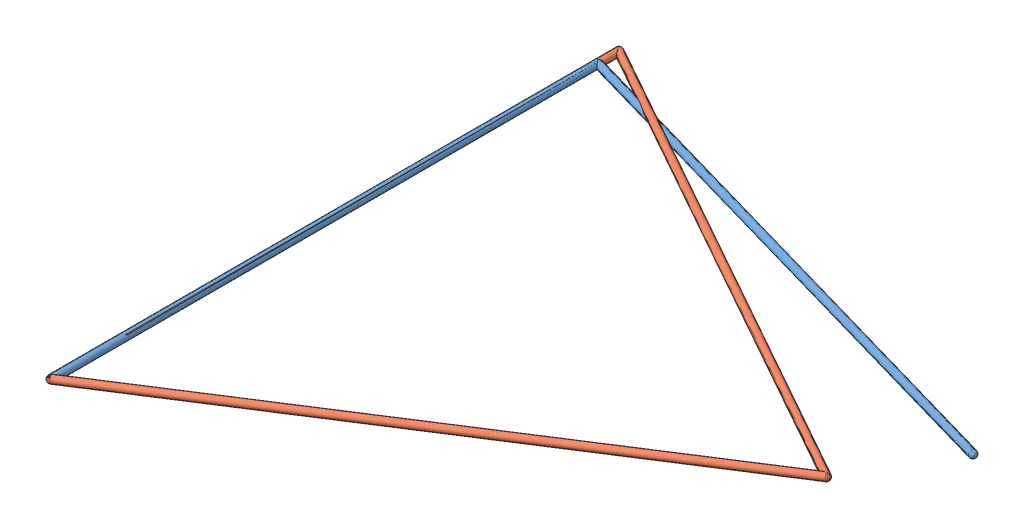
SolidWorks assembly dome_4v_model_1_major_triangle, configuration Default. Lengths in mm.
Overall size (1400.49 70.22 1512.1).
7 component instances, 2 part files, 2 mates.
Components (placement in the parent):
- dome_4v_model_1_D_triangle-1: dome_4v_model_1_D_triangle [Default] at (1132.4875 -174.6571 -806.7489) size (1398.91 19.05 1452.08)
  - dome_4v_D_model_1-1: dome_4v_D_model_1 [Default] at (627.7399 1152.8382 797.9864) size (19.05 19.05 1449.82)
  - dome_4v_D_model_1-2: dome_4v_D_model_1 [Default] at (627.7399 1152.8382 797.9864) x (0.275637 0 -0.961262) z (0.961262 0 0.275637) size (19.05 19.05 1449.82)
- dome_4v_model_1_E_triangle-1: dome_4v_model_1_E_triangle [Default] at (1244.9756 -152.5457 -1008.9741) size (1312.57 70.22 1512.1)
  - dome_4v_E_model_1-1: dome_4v_E_model_1 [Default] at (515.2518 1130.7268 945.0848) size (19.05 19.05 1504.95)
  - dome_4v_E_model_1-2: dome_4v_E_model_1 [Default] at (515.2518 1130.7268 2430.9848) x (0.037678 -0.999287 -0.002331) z (0.865366 0.033795 -0.5) size (19.05 19.05 1504.95)
  - dome_4v_E_model_1-3: dome_4v_E_model_1 [Default] at (515.2518 1130.7268 945.0848) x (0.500257 0.00098 -0.865877) z (0.865366 0.033795 0.5) size (19.05 19.05 1504.95)
Mates (geometry in assembly coordinates):
- Concentric3: concentric: sphere of dome_4v_model_1_D_triangle-1/dome_4v_D_model_1-2; sphere of dome_4v_model_1_E_triangle-1/dome_4v_E_model_1-3
- Concentric5: concentric: sphere of dome_4v_model_1_D_triangle-1/dome_4v_D_model_1-1; sphere of dome_4v_model_1_E_triangle-1/dome_4v_E_model_1-2
